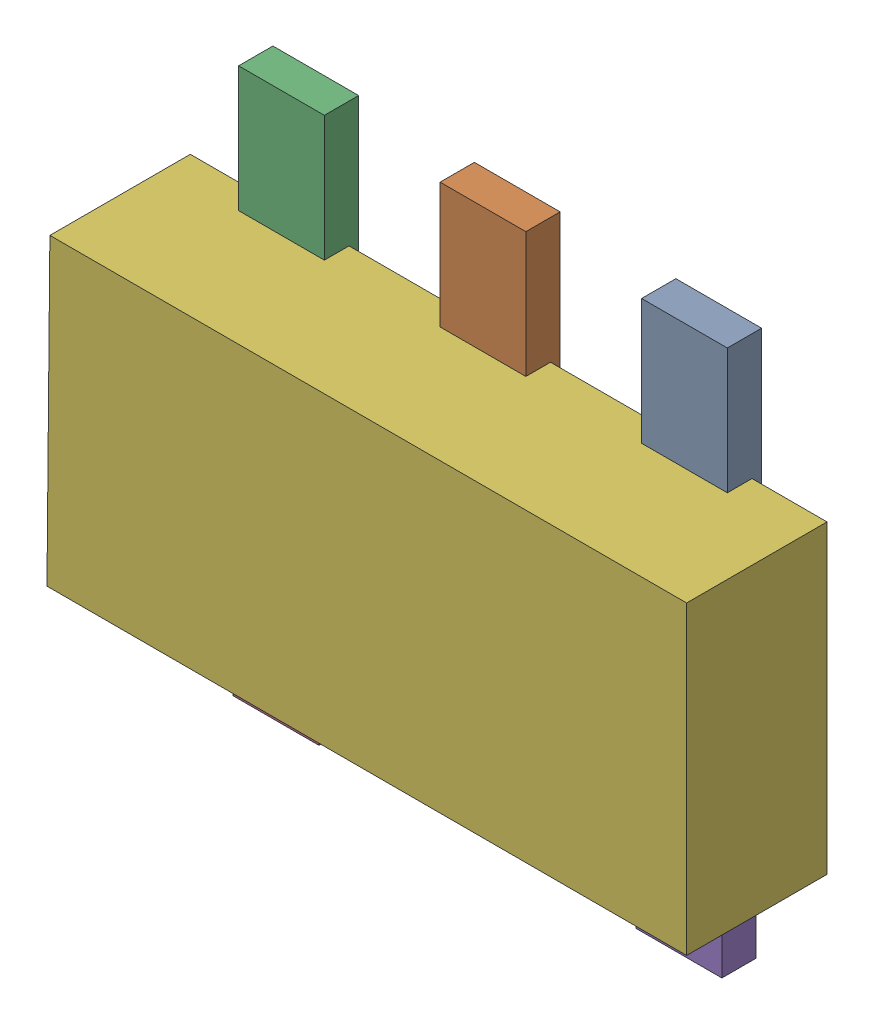
SolidWorks assembly U5, configuration Default. Lengths in mm.
Overall size (2.98 2.56 0.7).
12 component instances, 2 part files, 0 mates.
Components (placement in the parent):
- 744578800_5-1: 744578800_5 [Default] at (25.1108 19.5654 0) size (0.4 1.17 0.16)
  - Extruded (42)-1: Extruded (42) [Default] at origin size (0.4 1.17 0.16)
- 744578800_6-1: 744578800_6 [Default] at (24.171 19.5654 0) size (0.4 1.17 0.16)
  - Extruded (42)-1: Extruded (42) [Default] at origin size (0.4 1.17 0.16)
- 744578800_7-1: 744578800_7 [Default] at (23.2312 19.5654 0) size (0.4 1.17 0.16)
  - Extruded (42)-1: Extruded (42) [Default] at origin size (0.4 1.17 0.16)
- 744578800_8-1: 744578800_8 [Default] at (23.2058 18.1762 0) size (0.4 1.17 0.16)
  - Extruded (42)-1: Extruded (42) [Default] at origin size (0.4 1.17 0.16)
- 744578800_9-1: 744578800_9 [Default] at (25.0854 18.1762 0) size (0.4 1.17 0.16)
  - Extruded (42)-1: Extruded (42) [Default] at origin size (0.4 1.17 0.16)
- 1550848384_1-1: 1550848384_1 [Default] at (24.1691 18.8527 0.045) size (2.98 1.42 0.65)
  - Extruded (43)-1: Extruded (43) [Default] at origin size (2.98 1.42 0.65)
